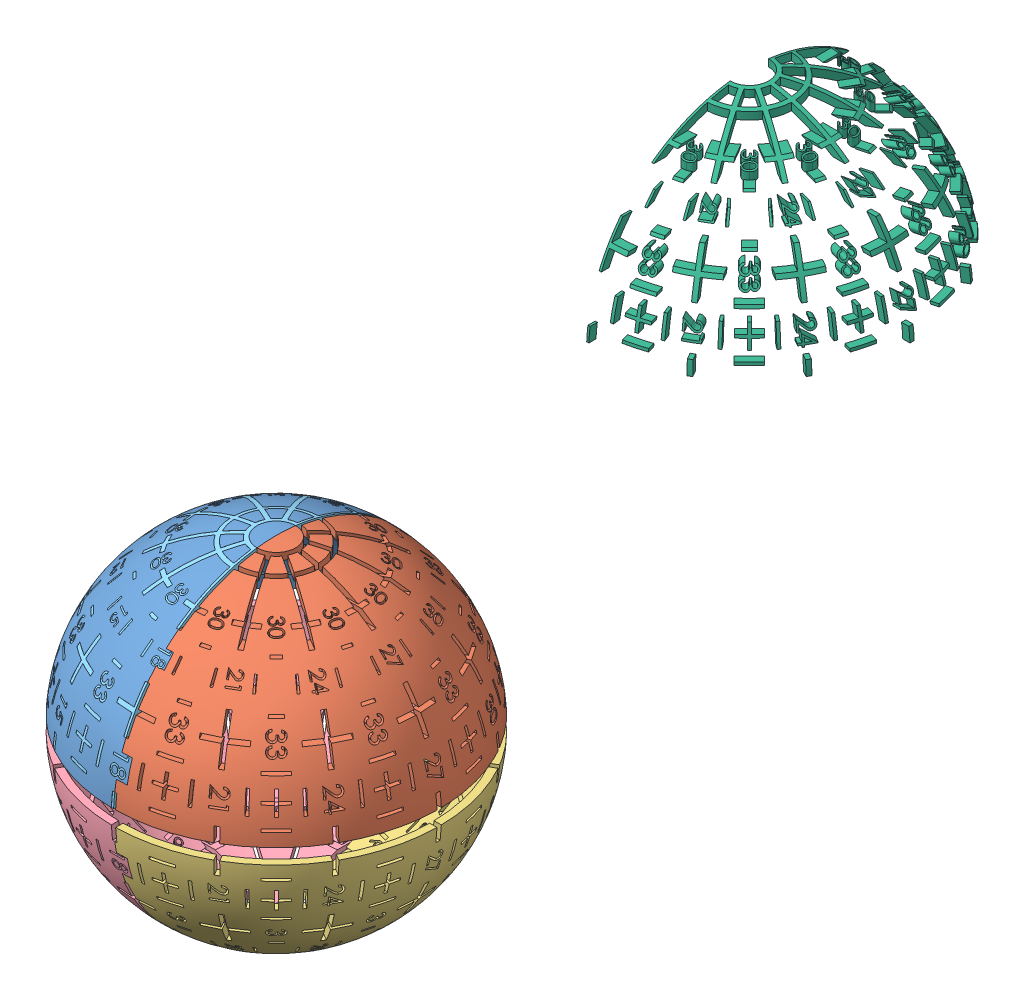
SolidWorks assembly puzzle, configuration Default. Lengths in mm.
Overall size (129.23 158.78 204.33).
6 component instances, 6 part files, 10 mates.
Components (placement in the parent):
- TopWhiteOuter-1: TopWhiteOuter [Default] at (34.8611 45.3576 67.9155) size (47.25 42.35 88.79)
- TopBlackOuter-1: TopBlackOuter [Default] at (34.8611 45.3576 67.9155) size (44.4 42.35 88.79)
- BottomBlackOuter-1: BottomBlackOuter [Default] at (34.8611 45.4576 67.9155) x (0.5 0 -0.866025) z (-0.866025 0 -0.5) size (82.56 42.35 66.43)
- BottomWhiteOuter-1: BottomWhiteOuter [Default] at (34.8611 45.4576 67.9155) x (0.5 0 -0.866025) z (-0.866025 0 -0.5) size (83.48 42.35 68.61)
- TopPlug-1: TopPlug [Default] at (34.8611 45.4076 67.9155) size (46.59 42.35 88.71)
- TopPlugWhite-1: TopPlugWhite [Default] at (59.0887 115.3845 -36.8197) size (44.35 42.35 88.71)
Mates (geometry in assembly coordinates):
- Coincident1: coincident: circle of TopWhiteOuter-1; circle of TopBlackOuter-1
- Coincident5: coincident: plane of TopWhiteOuter-1 through (34.8611 47.4576 67.9155) normal (0 -1 0); plane of TopBlackOuter-1 through (34.8611 47.4576 67.9155) normal (0 -1 0)
- Distance1: distance = 4.1 mm: plane of BottomBlackOuter-1 through (34.8611 43.3576 67.9155) normal (0 1 0); plane of TopBlackOuter-1 through (34.8611 47.4576 67.9155) normal (0 -1 0)
- Coincident7: coincident: plane of TopBlackOuter-1 through (35.448 51.2096 112.3655) normal (-1 0 0); plane of BottomBlackOuter-1 through (35.448 39.6057 112.3655) normal (-1 0 0)
- Concentric1: concentric: circle of TopBlackOuter-1; circle of BottomBlackOuter-1
- Concentric2: concentric: circle of TopWhiteOuter-1; circle of BottomWhiteOuter-1
- Coincident10: coincident: plane of BottomBlackOuter-1 through (34.8611 45.4576 128.5623) normal (-1 0 0); plane of BottomWhiteOuter-1 through (34.8611 45.4576 128.5623) normal (1 0 0)
- Coincident12: coincident: plane of BottomBlackOuter-1 through (34.8611 43.3576 67.9155) normal (0 1 0); plane of BottomWhiteOuter-1 through (34.8611 43.3576 67.9155) normal (0 1 0)
- Concentric3: concentric: circle of TopBlackOuter-1; circle of TopPlug-1
- Coincident13: coincident: plane of TopBlackOuter-1 through (34.8611 47.4576 67.9155) normal (0 -1 0); plane of TopPlug-1 through (93.9891 47.4576 23.5155) normal (0 -1 0)
